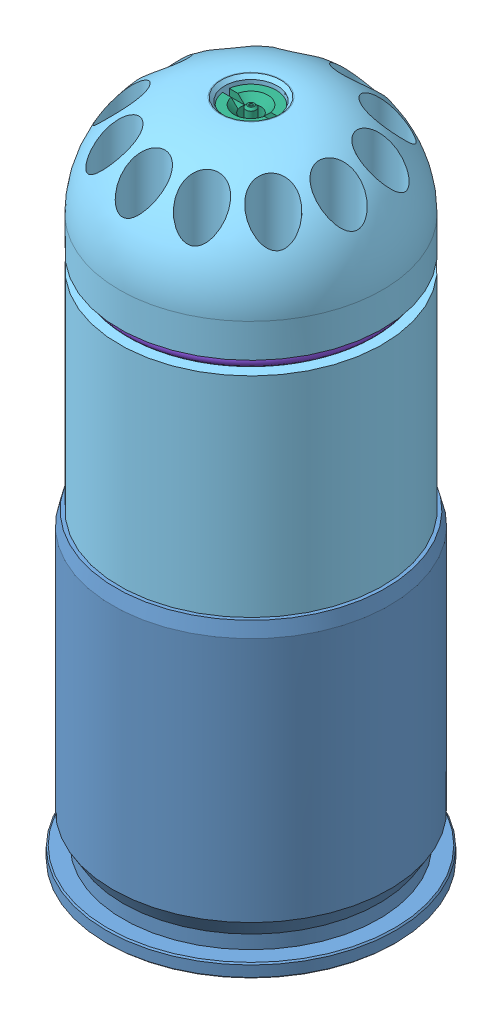
SolidWorks assembly 40mm-Klein, configuration Standard. Lengths in mm.
Overall size (51.21 98 51.21).
11 component instances, 8 part files, 20 mates.
Components (placement in the parent):
- Boden-G-1: Boden-G [Standard] at (-10.8436 -22.8172 45) size (42.9 45 42.9)
- Drücker-G-1: Drücker-G [Standard] at (-10.8436 -22.8172 45) size (14 23 14)
- value-1: value [Standard] at (-10.8436 -4.0172 45) size (20 21.5 20)
- Lock-Kugel-1: Lock-Kugel [Standard] at (-10.8436 -3.0172 55) size (4 4 4)
- Lock-Kugel-2: Lock-Kugel [Standard] at (-0.8436 -3.0172 45) size (4 4 4)
- Lock-Kugel-3: Lock-Kugel [Standard] at (-20.8436 -3.0172 45) size (4 4 4)
- Lock-Kugel-4: Lock-Kugel [Standard] at (-10.8436 -3.0172 35) size (4 4 4)
- Vorn-1: Vorn [Standard] at (-10.8436 5.6828 45) x (0.99501 0 0.099776) z (-0.099776 0 0.99501) size (39 69.5 39)
- Einfüllventil-1: Einfüllventil [Standard] at (-10.8436 61.6828 45) size (7.5 12.5 7.5)
- value-gegen-1: value-gegen [Standard] at (-10.8436 11.4828 45) x (1 0 -0.000025) z (0.000025 0 1) size (17.5 18.5 17.5)
- O-Ring oben-1: O-Ring oben [Standard] at (-10.8436 54.1828 45) x (-0.837169 0 -0.546944) z (-0.546944 0 0.837169) size (37 2 37)
Mates (geometry in assembly coordinates):
- Konzentrisch1: concentric anti-aligned: cylinder of Boden-G-1 through (-10.8436 -21.8172 45) axis (0 1 0) radius 7; cylinder of Drücker-G-1 through (-10.8436 -12.8172 45) axis (0 -1 0) radius 7
- Deckungsgleich1: coincident aligned: plane of Boden-G-1 through (-10.8436 -22.8172 45) normal (0 -1 0); plane of Drücker-G-1 through (-10.8436 -22.8172 45) normal (0 -1 0)
- Konzentrisch2: concentric: cylinder of value-1 through (-10.8436 49.628 35) axis (0 0 1) radius 2; sphere of Lock-Kugel-1
- Tangential2: tangent: curve of value-1; sphere of Lock-Kugel-1
- Konzentrisch3: concentric: cylinder of value-1 through (-20.8436 49.628 45) axis (1 0 0) radius 2; sphere of Lock-Kugel-2
- Tangential4: tangent: curve of value-1; sphere of Lock-Kugel-2
- Konzentrisch4: concentric: cylinder of value-1 through (-10.8436 49.628 35) axis (0 0 1) radius 2; sphere of Lock-Kugel-4
- Tangential6: tangent: curve of value-1; sphere of Lock-Kugel-4
- Konzentrisch5: concentric: cylinder of value-1 through (-20.8436 49.628 45) axis (1 0 0) radius 2; sphere of Lock-Kugel-3
- Tangential8: tangent: edge_curve of ?; unknown of ?
- Deckungsgleich2: coincident aligned: circle of Boden-G-1; cylinder of value-1 through (-10.8436 55.628 45) axis (0 -1 0) radius 10
- Konzentrisch6: concentric anti-aligned: cylinder of Vorn-1 through (-10.8436 56.328 45) axis (0 1 0) radius 2; cylinder of Einfüllventil-1 through (-10.8436 122.828 45) axis (0 -1 0) radius 2
- Deckungsgleich3: coincident anti-aligned: plane of Vorn-1 through (-10.8436 122.828 45) normal (0 1 0); plane of Einfüllventil-1 through (-10.8436 122.828 45) normal (0 -1 0)
- Deckungsgleich4: coincident anti-aligned: plane of Vorn-1 through (-10.8436 64.128 45) normal (0 -1 0); plane of value-gegen-1 through (-10.8436 64.128 45) normal (0 1 0)
- Konzentrisch7: concentric aligned: cylinder of Vorn-1 through (-10.8436 113.328 45) axis (0 -1 0) radius 7.5; cylinder of value-gegen-1 through (-10.8436 80.628 45) axis (0 -1 0) radius 7.5
- Deckungsgleich5: coincident anti-aligned: plane of value-1 through (-10.8436 62.128 45) normal (0 1 0); plane of value-gegen-1 through (-10.8436 62.128 45) normal (0 -1 0)
- Konzentrisch8: concentric aligned: cylinder of value-1 through (-10.8436 68.128 45) axis (0 -1 0) radius 4.95; cylinder of value-gegen-1 through (-10.8436 69.928 45) axis (0 -1 0) radius 5
- Deckungsgleich6: coincident anti-aligned: plane of Boden-G-1 through (-10.8436 22.1828 45) normal (0 1 0); plane of Vorn-1 through (-10.8436 22.1828 45) normal (0 -1 0)
- Tangential9: tangent: plane of Vorn-1 through (-32.7123 53.1828 42.8071) normal (0 1 0); torus of O-Ring oben-1
- Tangential10: tangent: cylinder of Vorn-1 through (-10.8436 75.1828 45) axis (0 1 0) radius 16.5; edge_curve of ?
